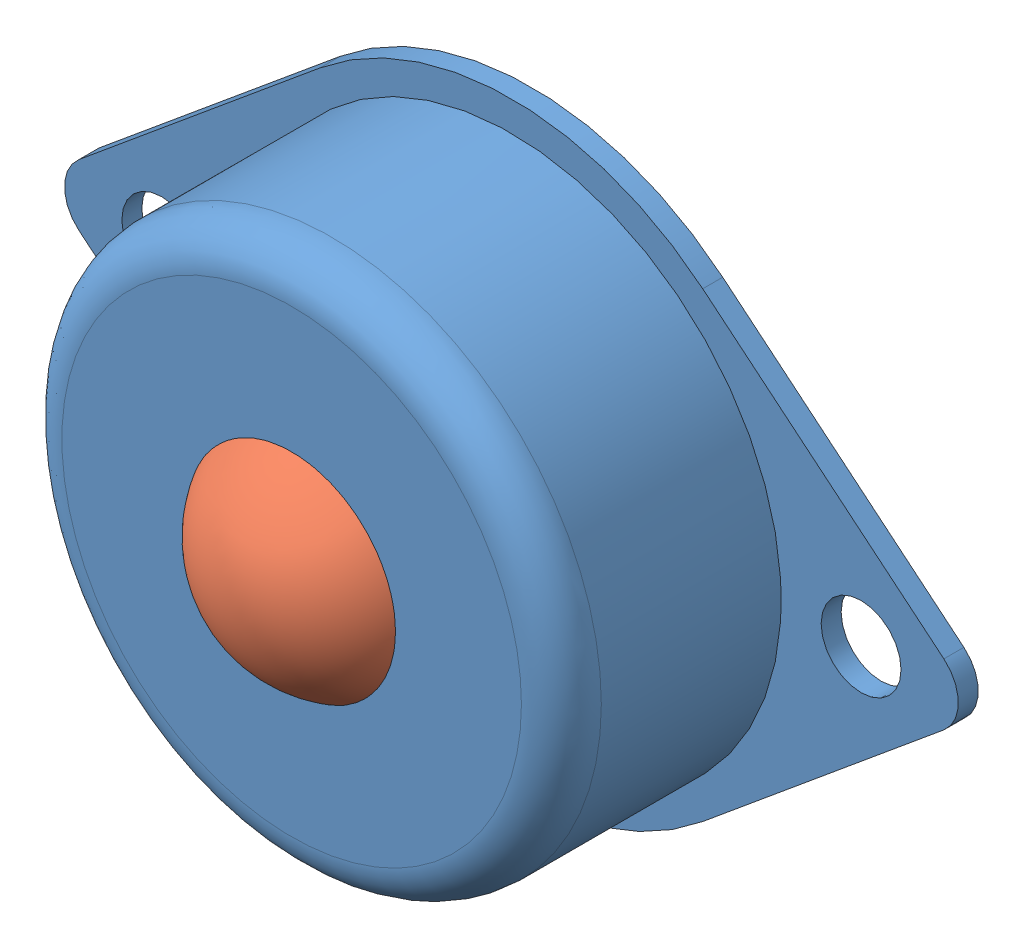
SolidWorks assembly 牛眼轮, configuration 默认. Lengths in mm.
Overall size (44.73 30 18.08).
2 component instances, 2 part files, 1 mates.
Components (placement in the parent):
- 牛眼轮框-1: 牛眼轮框 [默认] at (-49.0796 22.7542 -8) size (44.73 30 12)
- 牛眼轮心-1: 牛眼轮心 [默认] at (-49.0796 22.7542 1) x (-0.979339 -0.032906 -0.199531) z (0.194354 -0.425767 -0.883713) size (12 12 12)
Mates (geometry in assembly coordinates):
- 同心3: concentric: sphere of 牛眼轮框-1; sphere of 牛眼轮心-1
